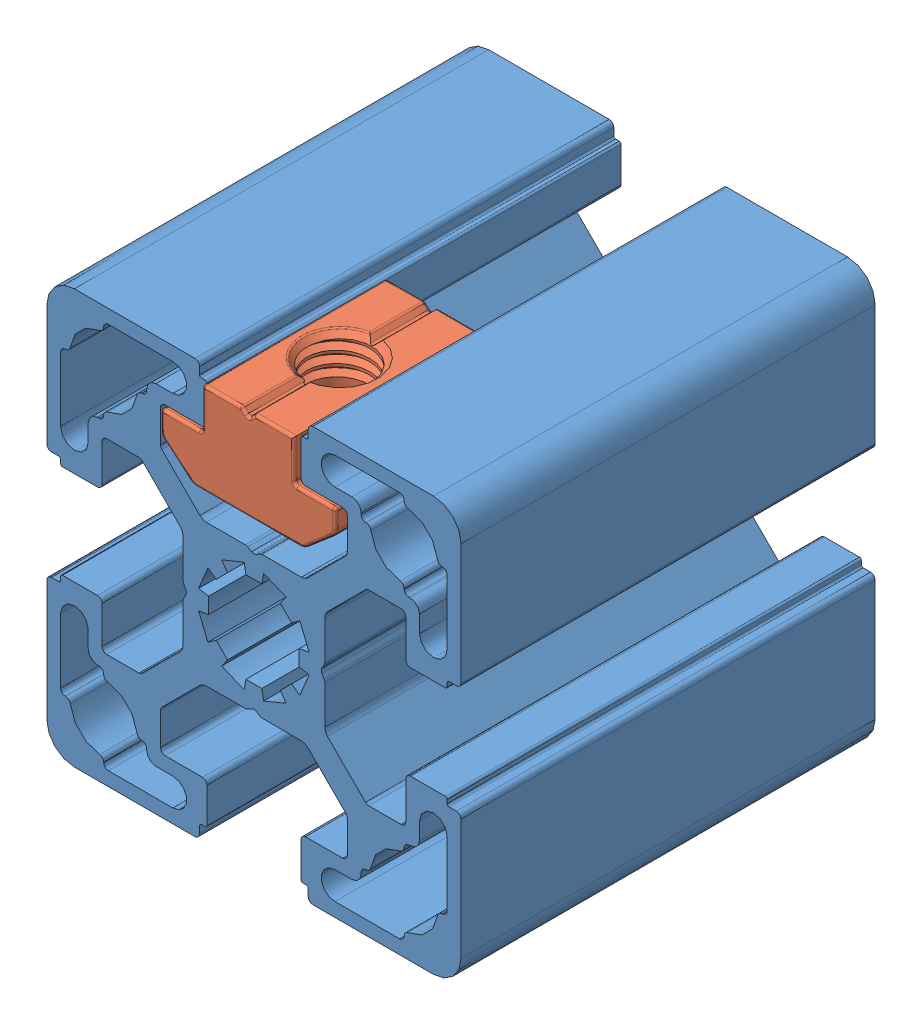
SolidWorks assembly Сборка Т-Сухарь 10 паз усиленный, configuration По умолчанию. Lengths in mm.
Overall size (45 45 45.54).
2 component instances, 2 part files, 2 mates.
Components (placement in the parent):
- 45х45-1: 45х45 [По умолчанию] at origin size (45 45 45)
- Т-Сухарь 10 паз усиленный-1: Т-Сухарь 10 паз усиленный [По умолчанию] at (-0.1 11 35.5381) size (19 10 20)
Mates (geometry in assembly coordinates):
- Совпадение1: coincident anti-aligned: plane of 45х45-1 through (0 16.5 45) normal (0 -1 0); plane of Т-Сухарь 10 паз усиленный-1 through (-9.6 16.5 25.5381) normal (0 1 0)
- Совпадение2: coincident anti-aligned: plane of 45х45-1 through (-5.1 0 45) normal (1 0 0); plane of Т-Сухарь 10 паз усиленный-1 through (-5.1 16.5 25.5381) normal (-1 0 0)
